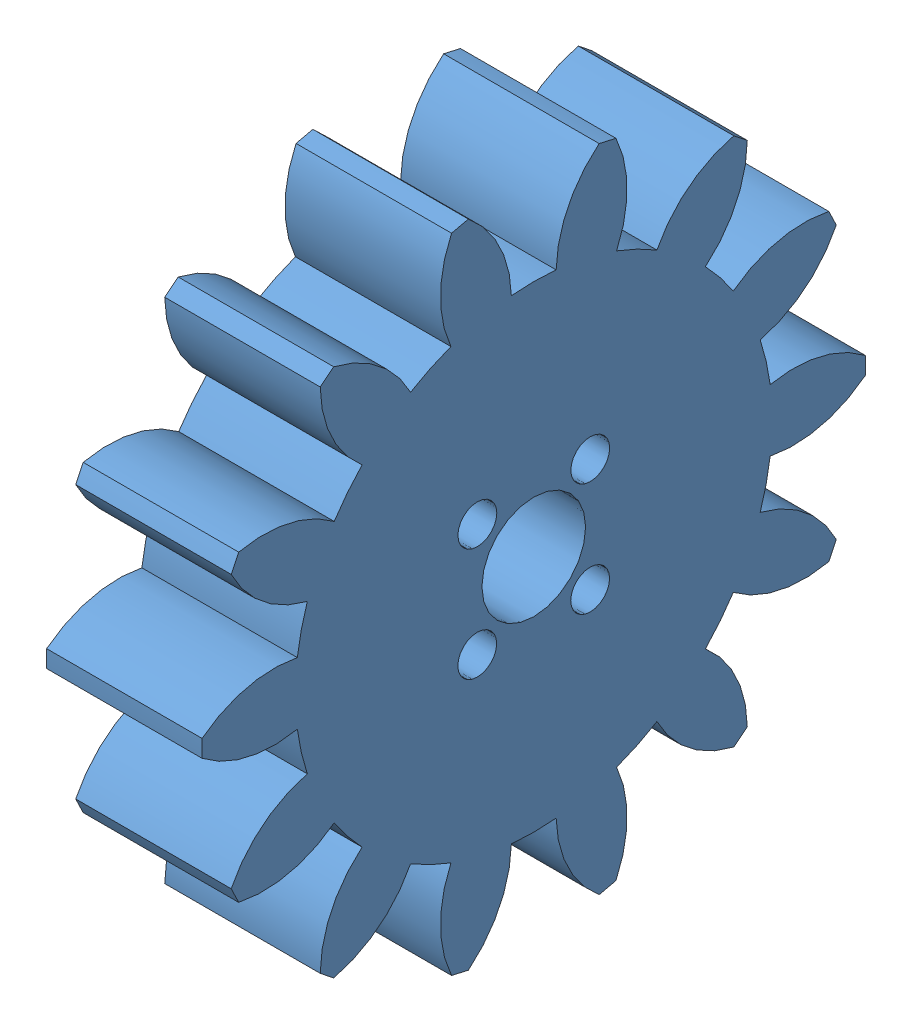
SolidWorks assembly ARMUS-REV2-500, configuration Défaut. Lengths in mm.
Overall size (28.58 79.69 81.28).
2 component instances, 2 part files, 4 mates.
Components (placement in the parent):
- ARMUS-REV2-501-1: ARMUS-REV2-501 [Défaut] at origin size (19.05 79.69 81.28)
- bore_set_screw_D_hub-1: bore_set_screw_D_hub [Défaut] at (-20.7023 -52.5937 -16.7801) x (0 -1 0.000796) z (0 0.000796 1) size (20.57 9.61 20.57)
Mates (geometry in assembly coordinates):
- Coincident1: coordinate: point of ARMUS-REV2-X01-1
- Concentric1: concentric anti-aligned: cylinder of ARMUS-REV2-X01-1 through (0 -6.91 6.921) axis (1 0 0) radius 2.3813; cylinder of bore_set_screw_D_hub-1 through (0 -6.91 6.921) axis (-1 0 0) radius 3.3722
- Concentric3: concentric anti-aligned: cylinder of ARMUS-REV2-X01-1 through (50.8001 0 0) axis (-1 0 0) radius 6.35; cylinder of bore_set_screw_D_hub-1 through (0 -0.0007 0.0007) axis (1 0 0) radius 3.175
- Coincident2: coincident anti-aligned: plane of ARMUS-REV2-X01-1 through (0 0 0) normal (-1 0 0); plane of bore_set_screw_D_hub-1 through (0 3.4539 -3.4594) normal (1 0 0)
